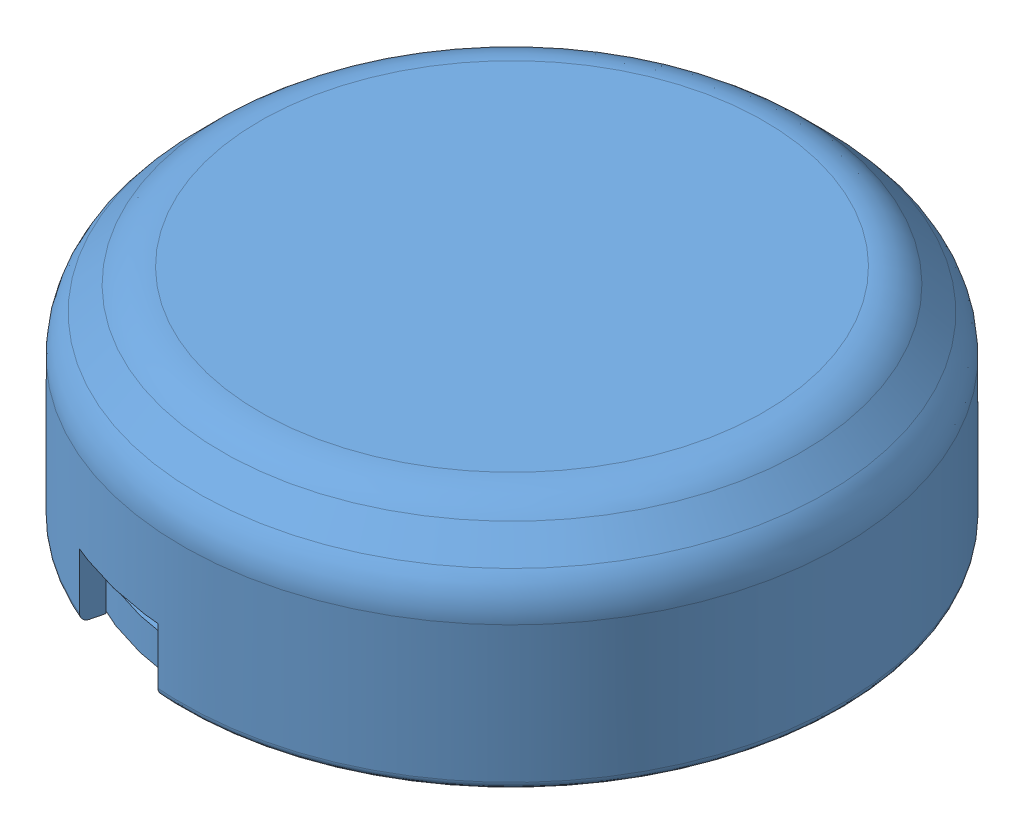
SolidWorks assembly Assembled Biocoin, configuration Default. Lengths in mm.
Overall size (37.88 10.56 37.88).
162 component instances, 39 part files, 5 mates.
Components (placement in the parent):
- Bottom - rev 1-1: Bottom - rev 1 [Default] at (11.776 12.857 23.582) size (30.23 5.59 30.23)
- DPV_PCB_v2.step-1: DPV_PCB_v2.step [Default] at (-1.1972 14.5285 10.4987) x (-0.000274 0 1) z (0 1 0) size (24.9 26.1 3.61)
  - Board.step-1: Board.step [Default] at origin size (24.9 26.1 0.96)
    - Open CASCADE STEP translator 6.8 1.1.1.step-1: Open CASCADE STEP translator 6.8 1.1.1.step [Default] at (0 0 -0.9603) size (24.9 26.1 0.96)
  - R13.step-1: R13.step [Default] at origin size (1.04 0.6 0.34)
    - User_Library-0402R.step-1: User_Library-0402R.step [Default] at (16.3069 1.397 0) x (1 0 0) z (0 -1 0) size (1.04 0.34 0.6)
  - IC4.step-1: IC4.step [Default] at origin size (0.78 0.78 0.38)
    - 6979170656.step-1: 6979170656.step [Default] at (8.3312 18.0086 0) x (-1 0 0) z (0 0 1) size (0.78 0.78 0.38)
      - Array.step-1: Array.step [Default] at origin size (0.66 0.66 0.26)
      - Body.step-1: Body.step [Default] at origin size (0.78 0.78 0.12)
  - R8.step-1: R8.step [Default] at origin size (1.04 0.6 0.34)
    - User_Library-0402R.step-1: User_Library-0402R.step [Default] at (7.3915 11.938 0) x (1 0 0) z (0 -1 0) size (1.04 0.34 0.6)
  - M2.step-1: M2.step [Default] at origin size (15.5 10.5 2.05)
    - MDBT50Q_3D_Drawing_20180620_RGB8421504.step-1: MDBT50Q_3D_Drawing_20180620_RGB8421504.step [Default] at (17.0122 12.9858 0.0128) x (0 -1 0) z (-1 0 0) size (10.5 2.05 15.5)
  - J6.step-1: J6.step [Default] at origin size (2.2 3.46 0.58)
    - 6979173296.step-1: 6979173296.step [Default] at (16.9418 14.4272 -0.9803) x (0 -1 0) z (1 0 0) size (3.46 0.58 2.2)
      - Open CASCADE STEP translator 6.8 1.6.1.1.step-1: Open CASCADE STEP translator 6.8 1.6.1.1.step [Default] at origin size (3.46 0.58 2.2)
      - Open CASCADE STEP translator 6.8 1.6.1.2.step-1: Open CASCADE STEP translator 6.8 1.6.1.2.step [Default] at origin
  - J5.step-1: J5.step [Default] at origin size (2.2 3.46 0.58)
    - 6979183456.step-1: 6979183456.step [Default] at (11.684 14.4272 -0.9803) x (0 1 0) z (-1 0 0) size (3.46 0.58 2.2)
      - Open CASCADE STEP translator 6.8 1.7.1.1.step-1: Open CASCADE STEP translator 6.8 1.7.1.1.step [Default] at origin size (3.46 0.58 2.2)
      - Open CASCADE STEP translator 6.8 1.7.1.2.step-1: Open CASCADE STEP translator 6.8 1.7.1.2.step [Default] at origin
  - L5.step-1: L5.step [Default] at origin size (0.5 1 0.25)
    - SW3dPS-d0402h025.step-1: SW3dPS-d0402h025.step [Default] at (2.4638 7.366 0) x (0 1 0) z (0 0 1) size (1 0.5 0.25)
  - MOSFET1.step-1: MOSFET1.step [Default] at origin size (0.81 0.81 0.39)
    - 6979167456.step-1: 6979167456.step [Default] at (3.8354 7.5946 0) x (0 -1 0) z (0 0 1) size (0.81 0.81 0.39)
  - U5.step-1: U5.step [Default] at origin size (2.1 2 0.55)
    - 6979170736.step-1: 6979170736.step [Default] at (7.3406 16.1036 0) size (2.1 2 0.55)
  - R12.step-1: R12.step [Default] at origin size (1.04 0.6 0.34)
    - User_Library-0402R.step-1: User_Library-0402R.step [Default] at (3.4289 15.3162 0) x (-1 0 0) z (0 1 0) size (1.04 0.34 0.6)
  - IC3.step-1: IC3.step [Default] at origin size (3.1 3 0.8)
    - 6979168976.step-1: 6979168976.step [Default] at (3.4798 17.7292 0) x (-1 0 0) z (0 0 1) size (3.1 3 0.8)
      - Body-0.step-1: Body-0.step [Default] at origin size (3 3 0.75)
      - ThermalPin.step-1: ThermalPin.step [Default] at (-0.825 -1.19 0) size (1.65 2.38 0.1)
      - PinsArrayLR.step-1: PinsArrayLR.step [Default] at origin size (3.1 1.75 0.1)
  - C30.step-1: C30.step [Default] at origin size (0.33 0.64 0.33)
    - 6979172816.step-1: 6979172816.step [Default] at (6.477 18.3388 0) x (0 1 0) z (0 0 1) size (0.64 0.33 0.33)
  - C28.step-1: C28.step [Default] at origin size (0.33 0.64 0.33)
    - 6979172816.step-1: 6979172816.step [Default] at (7.2898 18.3388 0) x (0 1 0) z (0 0 1) size (0.64 0.33 0.33)
  - U4.step-1: U4.step [Default] at origin size (2.44 2.12 1.11)
    - 6979179136.step-1: 6979179136.step [Default] at (7.366 20.193 0) x (-1 0 0) z (0 0 1) size (2.44 2.12 1.11)
  - R11.step-1: R11.step [Default] at origin size (0.6 1.04 0.34)
    - User_Library-0402R.step-1: User_Library-0402R.step [Default] at (11.2014 20.7519 0) x (0 1 0) z (1 0 0) size (1.04 0.34 0.6)
  - R10.step-1: R10.step [Default] at origin size (0.6 1.04 0.34)
    - User_Library-0402R.step-1: User_Library-0402R.step [Default] at (9.906 20.7519 0) x (0 1 0) z (1 0 0) size (1.04 0.34 0.6)
  - C27.step-1: C27.step [Default] at origin size (0.51 1.05 0.51)
    - User_Library-SMD_Ceramic_Capacitors_0402_(1005)_BB.step-1: User_Library-SMD_Ceramic_Capacitors_0402_(1005)_BB.step [Default] at (12.4928 20.7518 0) x (0 -1 0) z (0 0 1) size (1.05 0.51 0.51)
  - C26.step-1: C26.step [Default] at origin size (0.33 0.64 0.33)
    - 6979169616.step-1: 6979169616.step [Default] at (4.3434 21.717 0) x (0 -1 0) z (0 0 1) size (0.64 0.33 0.33)
  - C25.step-1: C25.step [Default] at origin size (0.33 0.64 0.33)
    - 6979169616.step-1: 6979169616.step [Default] at (12.5984 25.1206 0) x (0 -1 0) z (0 0 1) size (0.64 0.33 0.33)
  - U3.step-1: U3.step [Default] at origin size (2.59 1.09 0.56)
    - 6979170016.step-1: 6979170016.step [Default] at (15.4003 24.6078 0) x (0 -1 0) z (0 0 1) size (1.09 2.59 0.56)
  - R9.step-1: R9.step [Default] at origin size (1.04 0.6 0.34)
    - User_Library-0402R.step-1: User_Library-0402R.step [Default] at (7.3915 13.1826 0) x (1 0 0) z (0 -1 0) size (1.04 0.34 0.6)
  - IC2.step-1: IC2.step [Default] at origin size (0.95 1.49 0.53)
    - 6979176416.step-1: 6979176416.step [Default] at (5.08 12.9794 0) x (-1 0 0) z (0 0 1) size (0.95 1.49 0.53)
      - Array-1.step-1: Array-1.step [Default] at origin size (0.65 1.05 0.25)
      - Body-2.step-1: Body-2.step [Default] at origin size (0.95 1.49 0.28)
  - C24.step-1: C24.step [Default] at origin size (0.64 0.33 0.33)
    - 6979180736.step-1: 6979180736.step [Default] at (7.3914 14.3002 0) x (-1 0 0) z (0 0 1) size (0.64 0.33 0.33)
  - L4.step-1: L4.step [Default] at origin size (0.5 1 0.25)
    - SW3dPS-d0402h025.step-1: SW3dPS-d0402h025.step [Default] at (1.2446 10.1092 0) x (0 1 0) z (0 0 1) size (1 0.5 0.25)
  - C13.step-1: C13.step [Default] at origin size (0.33 0.64 0.33)
    - 6979169616.step-1: 6979169616.step [Default] at (5.08 21.717 0) x (0 -1 0) z (0 0 1) size (0.64 0.33 0.33)
  - U2.step-1: U2.step [Default] at origin size (2.44 2.12 1.11)
    - 6979179136.step-1: 6979179136.step [Default] at (7.366 22.6568 0) x (-1 0 0) z (0 0 1) size (2.44 2.12 1.11)
  - R7.step-1: R7.step [Default] at origin size (0.6 1.04 0.34)
    - User_Library-0402R.step-1: User_Library-0402R.step [Default] at (11.2014 22.9363 0) x (0 1 0) z (1 0 0) size (1.04 0.34 0.6)
  - R5.step-1: R5.step [Default] at origin size (0.6 1.04 0.34)
    - User_Library-0402R.step-1: User_Library-0402R.step [Default] at (9.906 22.9363 0) x (0 1 0) z (1 0 0) size (1.04 0.34 0.6)
  - C12.step-1: C12.step [Default] at origin size (0.51 1.05 0.51)
    - User_Library-SMD_Ceramic_Capacitors_0402_(1005)_BB.step-1: User_Library-SMD_Ceramic_Capacitors_0402_(1005)_BB.step [Default] at (12.4928 22.9362 0) x (0 -1 0) z (0 0 1) size (1.05 0.51 0.51)
  - S2.step-1: S2.step [Default] at origin size (2 2 0.65)
    - PMDPB58UPE,115.step-1: PMDPB58UPE,115.step [Default] at (3.2004 10.0076 0.0128) x (0 1 0) z (1 0 0) size (2 0.65 2)
  - J2.step-1: J2.step [Default] at origin size (1.83 3.81 1)
    - 6983029888.step-1: 6983029888.step [Default] at (14.0716 2.4257 0) size (0.25 0.25 0.25)
      - Extruded.step-1: Extruded.step [Default] at origin size (0.25 0.25 0.25)
    - SDO_SOD-123FL_ONS.step-1: SDO_SOD-123FL_ONS.step [Default] at (13.9447 2.5526 0) x (0 1 0) z (0 0 1) size (3.81 1.83 1)
  - S1.step-1: S1.step [Default] at origin size (1.65 2.5 0.56)
    - 6979182816.step-1: 6979182816.step [Default] at (1.2192 13.3096 0) x (0 -1 0) z (0 0 1) size (2.5 1.65 0.56)
  - D1.step-1: D1.step [Default] at origin size (0.51 0.99 0.51)
    - 6979174176.step-1: 6979174176.step [Default] at (4.191 5.3086 0) x (0 1 0) z (0 0 1) size (0.99 0.51 0.51)
  - R6.step-1: R6.step [Default] at origin size (1.04 0.6 0.34)
    - User_Library-0402R.step-1: User_Library-0402R.step [Default] at (13.6825 6.731 0) x (-1 0 0) z (0 1 0) size (1.04 0.34 0.6)
  - L3.step-1: L3.step [Default] at origin size (2 1.97 1.2)
    - 6979182736.step-1: 6979182736.step [Default] at (10.8458 1.778 0) x (-1 0 0) z (0 0 1) size (2 1.97 1.2)
      - term1.step-1: term1.step [Default] at (-1 -0.8 0) size (0.5 1.6 1.2)
      - term2.step-1: term2.step [Default] at (0.5 -0.8 0) size (0.5 1.6 1.2)
      - Body.step-1: Body.step [Default] at (-0.5 -0.784 0.012) size (0.78 0.78 0.12)
  - IC1.step-1: IC1.step [Default] at origin size (1.77 1.77 0.5)
    - 6979167536.step-1: 6979167536.step [Default] at (10.795 6.223 0) x (0 1 0) z (0 0 1) size (1.77 1.77 0.5)
      - Array-3.step-1: Array-3.step [Default] at origin size (1.47 1.47 0.27)
      - Body-4.step-1: Body-4.step [Default] at origin size (1.77 1.77 0.23)
  - C23.step-1: C23.step [Default] at origin size (1.6 0.8 0.3)
    - SW3dPS-0603_SMD_Capacitor.step-1: SW3dPS-0603_SMD_Capacitor.step [Default] at (6.7429 5.5626 0) x (-1 0 0) z (0 1 0) size (1.6 0.3 0.8)
  - C22.step-1: C22.step [Default] at origin size (1.6 0.8 0.3)
    - SW3dPS-0603_SMD_Capacitor.step-1: SW3dPS-0603_SMD_Capacitor.step [Default] at (6.7565 3.683 0) x (-1 0 0) z (0 1 0) size (1.6 0.3 0.8)
  - C21.step-1: C21.step [Default] at origin size (0.51 1.05 0.51)
    - User_Library-SMD_Ceramic_Capacitors_0402_(1005)_BB.step-1: User_Library-SMD_Ceramic_Capacitors_0402_(1005)_BB.step [Default] at (9.9862 4.0386 0) x (0 1 0) z (0 0 1) size (1.05 0.51 0.51)
  - C20.step-1: C20.step [Default] at origin size (1.05 0.51 0.51)
    - User_Library-SMD_Ceramic_Capacitors_0402_(1005)_BB.step-1: User_Library-SMD_Ceramic_Capacitors_0402_(1005)_BB.step [Default] at (13.6826 5.584 0) size (1.05 0.51 0.51)
  - C19.step-1: C19.step [Default] at origin size (1.05 0.51 0.51)
    - User_Library-SMD_Ceramic_Capacitors_0402_(1005)_BB.step-1: User_Library-SMD_Ceramic_Capacitors_0402_(1005)_BB.step [Default] at (11.7348 4.195 0) x (-1 0 0) z (0 0 1) size (1.05 0.51 0.51)
  - J1.step-1: J1.step [Default] at origin size (4.2 4.3 1.45)
    - 6979183296.step-1: 6979183296.step [Default] at (17.7292 4.699 0) x (1 0 0) z (0 -1 0) size (4.2 1.45 4.3)
  - U1.step-1: U1.step [Default] at origin size (4.19 3.61 0.56)
    - 6979180096.step-1: 6979180096.step [Default] at (15.8088 21.6742 0) size (4.19 3.61 0.56)
  - RTIA1.step-1: RTIA1.step [Default] at origin size (1.04 0.6 0.34)
    - User_Library-0402R.step-1: User_Library-0402R.step [Default] at (19.6151 22.6394 0) x (-1 0 0) z (0 1 0) size (1.04 0.34 0.6)
  - RCAL1.step-1: RCAL1.step [Default] at origin size (0.33 0.64 0.33)
    - 6979169616.step-1: 6979169616.step [Default] at (11.6586 25.019 0) x (0 -1 0) z (0 0 1) size (0.64 0.33 0.33)
  - R4.step-1: R4.step [Default] at origin size (0.6 1.04 0.34)
    - User_Library-0402R.step-1: User_Library-0402R.step [Default] at (5.334 7.7645 0) x (0 1 0) z (1 0 0) size (1.04 0.34 0.6)
  - R3.step-1: R3.step [Default] at origin size (0.6 1.04 0.34)
    - User_Library-0402R.step-1: User_Library-0402R.step [Default] at (22.225 5.5627 0) x (0 1 0) z (1 0 0) size (1.04 0.34 0.6)
  - R2.step-1: R2.step [Default] at origin size (0.6 1.04 0.34)
    - User_Library-0402R.step-1: User_Library-0402R.step [Default] at (21.0312 5.5625 0) x (0 -1 0) z (-1 0 0) size (1.04 0.34 0.6)
  - R1.step-1: R1.step [Default] at origin size (0.6 1.04 0.34)
    - User_Library-0402R.step-1: User_Library-0402R.step [Default] at (5.3086 10.1601 0) x (0 1 0) z (1 0 0) size (1.04 0.34 0.6)
  - L2.step-1: L2.step [Default] at origin size (0.5 1 0.25)
    - SW3dPS-d0402h025.step-1: SW3dPS-d0402h025.step [Default] at (2.8956 13.081 0) x (0 -1 0) z (0 0 1) size (1 0.5 0.25)
  - L1.step-1: L1.step [Default] at origin size (1 0.5 0.25)
    - SW3dPS-d0402h025.step-1: SW3dPS-d0402h025.step [Default] at (4.0132 20.193 0) x (-1 0 0) z (0 0 1) size (1 0.5 0.25)
  - CTIA1.step-1: CTIA1.step [Default] at origin size (1.05 0.51 0.51)
    - User_Library-SMD_Ceramic_Capacitors_0402_(1005)_BB.step-1: User_Library-SMD_Ceramic_Capacitors_0402_(1005)_BB.step [Default] at (19.6152 21.5004 0) x (-1 0 0) z (0 0 1) size (1.05 0.51 0.51)
  - CLPF1.step-1: CLPF1.step [Default] at origin size (0.33 0.64 0.33)
    - 6979172816.step-1: 6979172816.step [Default] at (10.8204 24.9936 0) x (0 1 0) z (0 0 1) size (0.64 0.33 0.33)
  - C18.step-1: C18.step [Default] at origin size (0.51 1.05 0.51)
    - User_Library-SMD_Ceramic_Capacitors_0402_(1005)_BB.step-1: User_Library-SMD_Ceramic_Capacitors_0402_(1005)_BB.step [Default] at (7.8954 7.747 0) x (0 -1 0) z (0 0 1) size (1.05 0.51 0.51)
  - C17.step-1: C17.step [Default] at origin size (0.51 1.05 0.51)
    - User_Library-SMD_Ceramic_Capacitors_0402_(1005)_BB.step-1: User_Library-SMD_Ceramic_Capacitors_0402_(1005)_BB.step [Default] at (6.7524 10.152 0) x (0 -1 0) z (0 0 1) size (1.05 0.51 0.51)
  - C16.step-1: C16.step [Default] at origin size (0.51 1.05 0.51)
    - User_Library-SMD_Ceramic_Capacitors_0402_(1005)_BB.step-1: User_Library-SMD_Ceramic_Capacitors_0402_(1005)_BB.step [Default] at (7.8954 10.152 0) x (0 -1 0) z (0 0 1) size (1.05 0.51 0.51)
  - C15.step-1: C15.step [Default] at origin size (0.51 1.05 0.51)
    - User_Library-SMD_Ceramic_Capacitors_0402_(1005)_BB.step-1: User_Library-SMD_Ceramic_Capacitors_0402_(1005)_BB.step [Default] at (6.6254 7.747 0) x (0 -1 0) z (0 0 1) size (1.05 0.51 0.51)
  - C14.step-1: C14.step [Default] at origin size (0.64 0.33 0.33)
    - 6979180736.step-1: 6979180736.step [Default] at (21.2344 19.0754 0) x (-1 0 0) z (0 0 1) size (0.64 0.33 0.33)
  - C11.step-1: C11.step [Default] at origin size (1.05 0.51 0.51)
    - User_Library-SMD_Ceramic_Capacitors_0402_(1005)_BB.step-1: User_Library-SMD_Ceramic_Capacitors_0402_(1005)_BB.step [Default] at (19.6088 20.2558 0) x (-1 0 0) z (0 0 1) size (1.05 0.51 0.51)
  - C10.step-1: C10.step [Default] at origin size (0.64 0.33 0.33)
    - 6979183216.step-1: 6979183216.step [Default] at (9.398 24.638 0) size (0.64 0.33 0.33)
  - C9.step-1: C9.step [Default] at origin size (0.51 1.05 0.51)
    - User_Library-SMD_Ceramic_Capacitors_0402_(1005)_BB.step-1: User_Library-SMD_Ceramic_Capacitors_0402_(1005)_BB.step [Default] at (21.3146 20.7534 0) x (0 1 0) z (0 0 1) size (1.05 0.51 0.51)
  - C8.step-1: C8.step [Default] at origin size (0.64 0.33 0.33)
    - 6979180736.step-1: 6979180736.step [Default] at (19.05 23.6982 0) x (-1 0 0) z (0 0 1) size (0.64 0.33 0.33)
  - C7.step-1: C7.step [Default] at origin size (0.64 0.33 0.33)
    - 6979180736.step-1: 6979180736.step [Default] at (19.3184 19.0326 0) x (-1 0 0) z (0 0 1) size (0.64 0.33 0.33)
  - C6.step-1: C6.step [Default] at origin size (0.64 0.33 0.33)
    - 6979183216.step-1: 6979183216.step [Default] at (15.7988 19.0246 0) size (0.64 0.33 0.33)
  - C5.step-1: C5.step [Default] at origin size (0.64 0.33 0.33)
    - 6979180736.step-1: 6979180736.step [Default] at (14.351 19.0246 0) x (-1 0 0) z (0 0 1) size (0.64 0.33 0.33)
  - C4.step-1: C4.step [Default] at origin size (0.33 0.64 0.33)
    - 6979172816.step-1: 6979172816.step [Default] at (13.4112 25.1206 0) x (0 1 0) z (0 0 1) size (0.64 0.33 0.33)
  - C3.step-1: C3.step [Default] at origin size (0.64 0.33 0.33)
    - 6979183216.step-1: 6979183216.step [Default] at (12.5476 19.0246 0) size (0.64 0.33 0.33)
  - C2.step-1: C2.step [Default] at origin size (0.64 0.33 0.33)
    - 6979180736.step-1: 6979180736.step [Default] at (11.2014 19.0246 0) x (-1 0 0) z (0 0 1) size (0.64 0.33 0.33)
  - C1.step-1: C1.step [Default] at origin size (0.64 0.33 0.33)
    - 6979180736.step-1: 6979180736.step [Default] at (17.3228 19.0246 0) x (-1 0 0) z (0 0 1) size (0.64 0.33 0.33)
- Battery-1: Battery [Default] at (11.7885 16.6806 23.7195) size (24.5 5.51 24.5)
- Top - rev 1-1: Top - rev 1 [Default] at (11.776 12.857 23.582) x (-0.971151 0 -0.238467) z (0.238467 0 -0.971151) size (31.32 10.56 31.32)
Mates (geometry in assembly coordinates):
- Coincident2: coincident anti-aligned: plane of Bottom - rev 1-1 through (11.776 13.5682 23.582) normal (0 1 0); plane of DPV_PCB_v2.step-1/Board.step-1/Open CASCADE STEP translator 6.8 1.1.1.step-1 through (6.3229 13.5682 35.3498) normal (0 -1 0)
- Parallel1: parallel aligned: line of Bottom - rev 1-1 through (6.188 14.381 35.5497) axis (1 0 0); line of DPV_PCB_v2.step-1/Board.step-1/Open CASCADE STEP translator 6.8 1.1.1.step-1 through (6.3229 13.5682 35.3498) axis (1 0 0)
- Concentric1: concentric aligned: circle of Bottom - rev 1-1; circle of DPV_PCB_v2.step-1/Board.step-1/Open CASCADE STEP translator 6.8 1.1.1.step-1
- Coincident4: coincident aligned: plane of Bottom - rev 1-1 through (11.776 12.857 23.582) normal (0 -1 0); plane of Top - rev 1-1 through (11.776 12.857 23.582) normal (0 -1 0)
- Concentric7: concentric aligned: circle of Bottom - rev 1-1; circle of Top - rev 1-1
